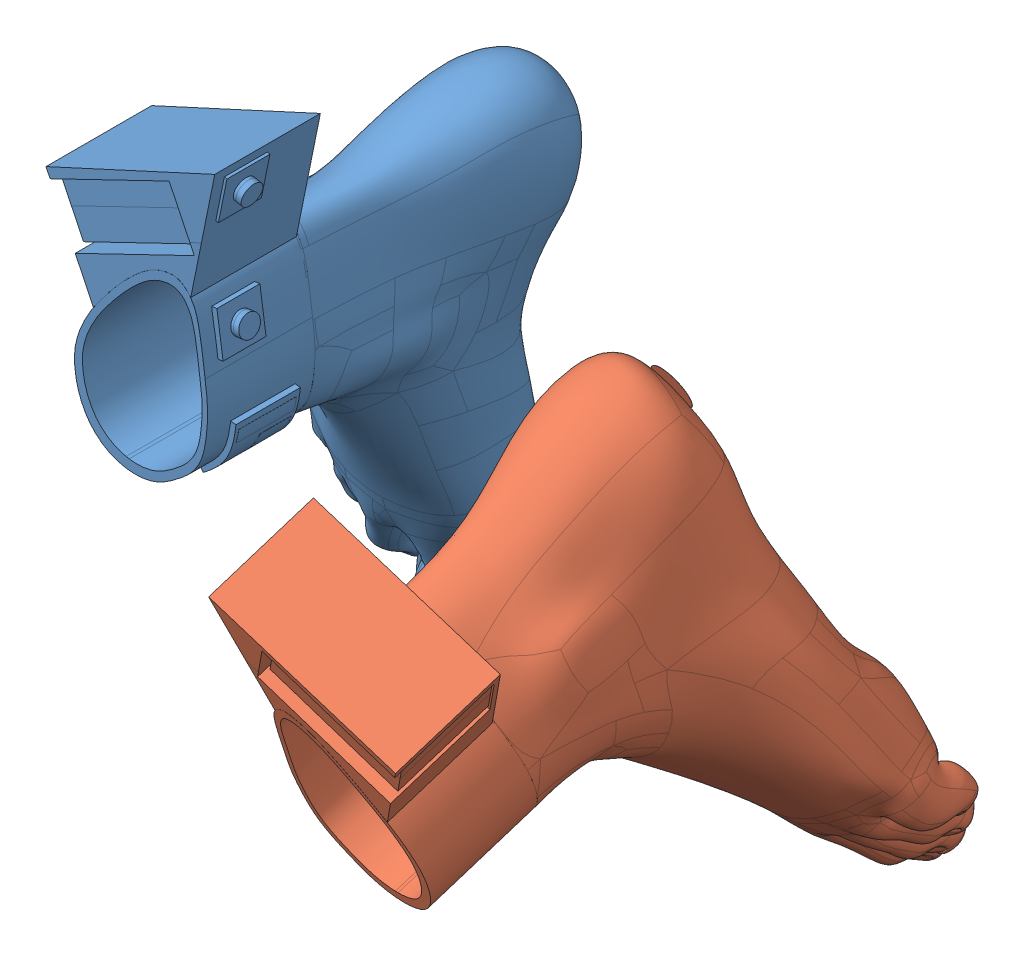
SolidWorks assembly Feet_toestep, configuration Default. Lengths in mm.
Overall size (564.51 790.64 567.17).
3 component instances, 3 part files, 0 mates.
Components (placement in the parent):
- foot1-1: foot1 [Right] at (256.4291 194.2322 323.4055) size (245.52 568.46 358.41)
- Mirrorfoot1-2: Mirrorfoot1 [Right] at (383.5709 194.2322 323.4055) x (-1 0 0) z (0 0 -1) (suppressed, hidden)
- Mirrorfoot1-4: Mirrorfoot1 [Right] at (232.3622 109.8935 280.2318) x (-0.996893 0.051658 -0.059457) z (0.074974 0.391038 -0.917316) size (245.52 568.46 358.41)
